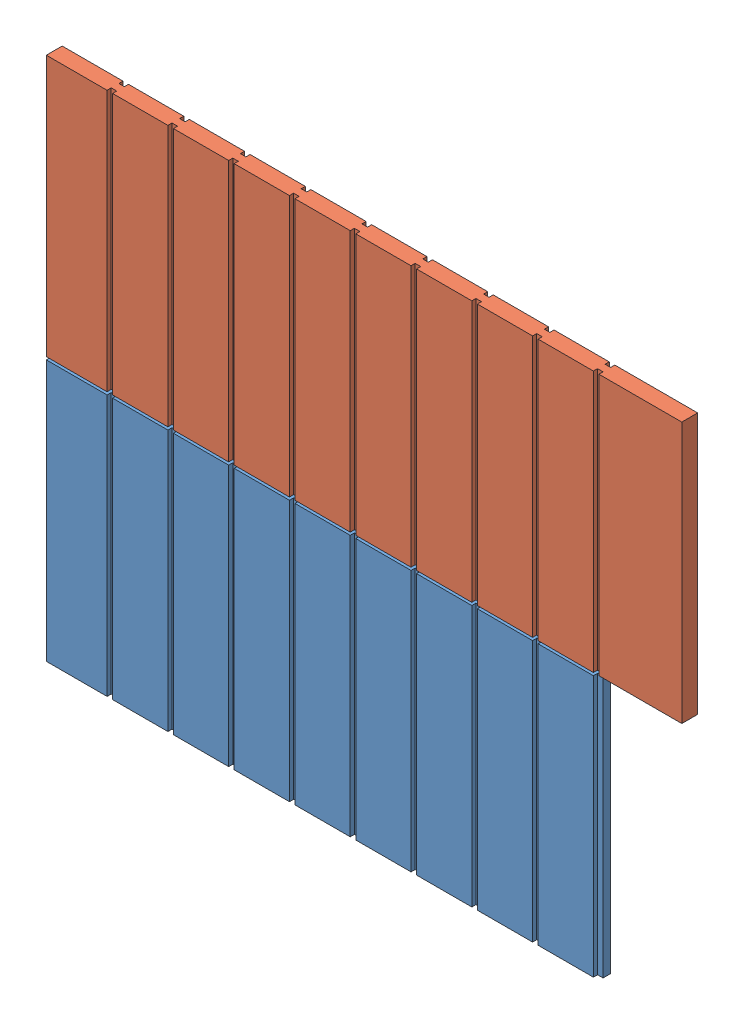
SolidWorks assembly Assem1, configuration Default. Lengths in mm.
Overall size (730.25 603.25 18.26).
2 component instances, 2 part files, 5 mates.
Components (placement in the parent):
- PartsCab_KeyboardDivider-1: PartsCab_KeyboardDivider [Default] at (-247.7055 -140.334 -9.1781) x (0 -1 0) z (0 0 1) size (300.04 635 18.26)
- PartsCab_ShortDivider-1: PartsCab_ShortDivider [Default] at (-247.7055 162.8785 -9.1781) x (0 -1 0) z (0 0 1) size (300.04 730.25 18.26)
Mates (geometry in assembly coordinates):
- Coincident1: coincident anti-aligned: plane of PartsCab_KeyboardDivider-1 through (-140.334 0 -18.2563) normal (0 -1 0)
- Distance1: distance = 3.175 mm anti-aligned: plane of PartsCab_ShortDivider-1 through (-140.334 303.2125 -18.2563) normal (0 -1 0); plane of PartsCab_KeyboardDivider-1 through (-140.334 300.0375 -18.2563) normal (0 1 0)
- Coincident2: coincident aligned: plane of PartsCab_KeyboardDivider-1 through (-140.334 1475.3167 -18.2563) normal (-1 0 0); plane of PartsCab_ShortDivider-1 through (-140.334 1778.5292 -18.2563) normal (-1 0 0)
- Coincident3: coincident aligned: plane of PartsCab_KeyboardDivider-1 through (224.791 737.6583 -18.2563) normal (0 0 -1); plane of PartsCab_ShortDivider-1 through (224.791 1040.8708 -18.2563) normal (0 0 -1)
- Coincident4: coincident aligned: plane of PartsCab_ShortDivider-1 through (224.791 1040.8708 0) normal (0 0 1)
